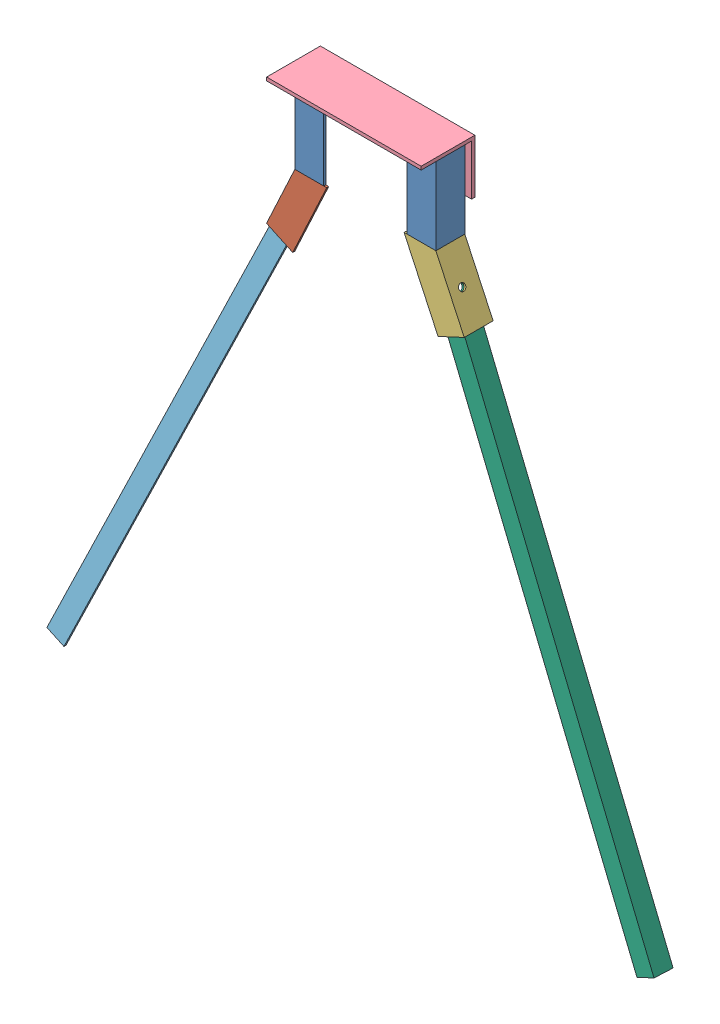
SolidWorks assembly БабкаЗСб, configuration По умолчанию. Lengths in mm.
Overall size (904.67 895.7 80).
7 component instances, 6 part files, 20 mates.
Components (placement in the parent):
- ПяткаЗБ40-1: ПяткаЗБ40 [По умолчанию] at (5.0293 120 -31.3165) x (0 -1 0) z (0 0 1) size (125 43 43)
- ПяткаЗБ40-2: ПяткаЗБ40 [По умолчанию] at (209.0293 120 -31.3165) x (0 -1 0) z (1 0 0) size (125 43 43)
- УкосЗБЛ40-1: УкосЗБЛ40 [По умолчанию] at (13.1841 11.8692 -31.3165) x (-0.421731 -0.906721 0) z (0 0 1) size (120 43 43)
- УкосЗБП40-1: УкосЗБП40 [По умолчанию] at (200.8746 11.8692 -31.3165) x (0.421731 -0.906721 0) z (0.906721 0.421731 0) size (120 43 43)
- ПяткаЗ75-1: ПяткаЗ75 [По умолчанию] at (-7.9707 120 -71.3165) x (1 0 0) z (0 0 -1) size (230 80 80)
- Нога1л-1: Нога1л [По умолчанию] at (-342.2193 -759.3616 -9.101) x (0.906721 -0.421731 0) z (0.421474 0.906169 -0.034899) size (28 28 800)
- Нога1п-1: Нога1п [По умолчанию] at (556.278 -759.3616 -9.101) x (0.014718 -0.031644 -0.999391) z (-0.421474 0.906169 -0.034899) size (28 28 800)
Mates (geometry in assembly coordinates):
- Совпадение4: coincident aligned: plane of ПяткаЗБ40-1 through (45.0293 -5 -28.3165) normal (0 0 1); plane of ПяткаЗБ40-2 through (209.0293 -5 -28.3165) normal (0 0 1)
- Совпадение5: coincident aligned: plane of ПяткаЗБ40-1 through (5.0293 120 -31.3165) normal (0 1 0); plane of ПяткаЗБ40-2 through (209.0293 120 -31.3165) normal (0 1 0)
- Расстояние1: distance = 210 mm anti-aligned: plane of ПяткаЗБ40-1 through (2.0293 -5 -31.3165) normal (-1 0 0); plane of ПяткаЗБ40-2 through (212.0293 -5 -71.3165) normal (1 0 0)
- Совпадение7: coincident aligned: plane of ПяткаЗБ40-1 through (45.0293 -5 -28.3165) normal (0 0 1); plane of УкосЗБЛ40-1 through (-1.1547 -113.8065 -28.3165) normal (0 0 1)
- Совпадение8: coincident anti-aligned: plane of ПяткаЗБ40-1 through (5.0293 -5 -31.3165) normal (0 -1 0); plane of УкосЗБЛ40-1 through (49.453 -5 -78.3165) normal (0 1 0)
- Совпадение9: coincident anti-aligned: line of ПяткаЗБ40-1 through (2.0293 -5 -28.3165) axis (0 0 -1); line of УкосЗБЛ40-1 through (2.0293 -5 -71.3165) axis (0 0 1)
- Совпадение10: coincident aligned: plane of УкосЗБЛ40-1 through (-1.1547 -113.8065 -28.3165) normal (0 0 1); plane of УкосЗБП40-1 through (251.4823 -96.9373 -28.3165) normal (0 0 1)
- Совпадение11: coincident aligned: line of ПяткаЗБ40-2 through (212.0293 -5 -71.3165) axis (0 0 1); line of УкосЗБП40-1 through (212.0293 -5 -71.3165) axis (0 0 1)
- Совпадение12: coincident anti-aligned: plane of ПяткаЗБ40-2 through (209.0293 -5 -31.3165) normal (0 -1 0); plane of УкосЗБП40-1 through (164.6057 -5 -78.3165) normal (0 1 0)
- Совпадение13: coincident anti-aligned: plane of ПяткаЗБ40-1 through (5.0293 120 -31.3165) normal (0 1 0); plane of ПяткаЗ75-1 through (222.0293 120 -71.3165) normal (0 -1 0)
- Совпадение14: coincident anti-aligned: plane of ПяткаЗБ40-1 through (5.0293 -5 -71.3165) normal (0 0 -1); plane of ПяткаЗ75-1 through (222.0293 120 -71.3165) normal (0 0 1)
- Расстояние2: distance = 10 mm aligned: plane of ПяткаЗ75-1 through (222.0293 120 -71.3165) normal (1 0 0); plane of ПяткаЗБ40-2 through (212.0293 -5 -71.3165) normal (1 0 0)
- Совпадение15: coincident anti-aligned: plane of УкосЗБЛ40-1 through (-37.4236 -96.9373 -31.3165) normal (0.906721 -0.421731 0); plane of Нога1л-1 through (-8.1283 -33.9525 -62.0053) normal (-0.906721 0.421731 0)
- Совпадение17: coincident: line of УкосЗБЛ40-1 through (-1.1547 -113.8065 -31.3165) axis (-0.906721 0.421731 0); plane of Нога1л-1
- Концентричный1: concentric aligned: cylinder of УкосЗБЛ40-1 through (-9.99 -54.5534 -46.3165) axis (-0.906721 0.421731 0) radius 5; cylinder of Нога1л-1 through (-7.2698 -55.8186 -46.3165) axis (-0.906721 0.421731 0) radius 5
- Концентричный2: concentric aligned: cylinder of УкосЗБП40-1 through (224.0487 -54.5534 -46.3165) axis (0.906721 0.421731 0) radius 5; cylinder of Нога1п-1 through (221.3285 -55.8186 -46.3165) axis (0.906721 0.421731 0) radius 5
- Совпадение18: coincident anti-aligned: plane of УкосЗБП40-1 through (251.4823 -96.9373 -71.3165) normal (-0.906721 -0.421731 0); plane of Нога1п-1 through (221.8191 -33.1614 -37.0206) normal (0.906721 0.421731 0)
- Совпадение19: coincident: line of УкосЗБП40-1 through (241.4823 -96.9373 -31.3165) axis (-0.906721 -0.421731 0); plane of Нога1п-1
- Угол1: planar angle = 3.106686 rad anti-aligned: plane of Нога1п-1 through (196.3867 -44.875 -34.0224) normal (-0.014718 0.031644 0.999391); plane of УкосЗБП40-1 through (251.4823 -96.9373 -28.3165) normal (0 0 1)
- Угол2: planar angle = 3.106686 rad anti-aligned: plane of Нога1л-1 through (-4.9961 -34.3317 -34.0224) normal (0.014718 0.031644 0.999391); plane of УкосЗБЛ40-1 through (-1.1547 -113.8065 -28.3165) normal (0 0 1)
